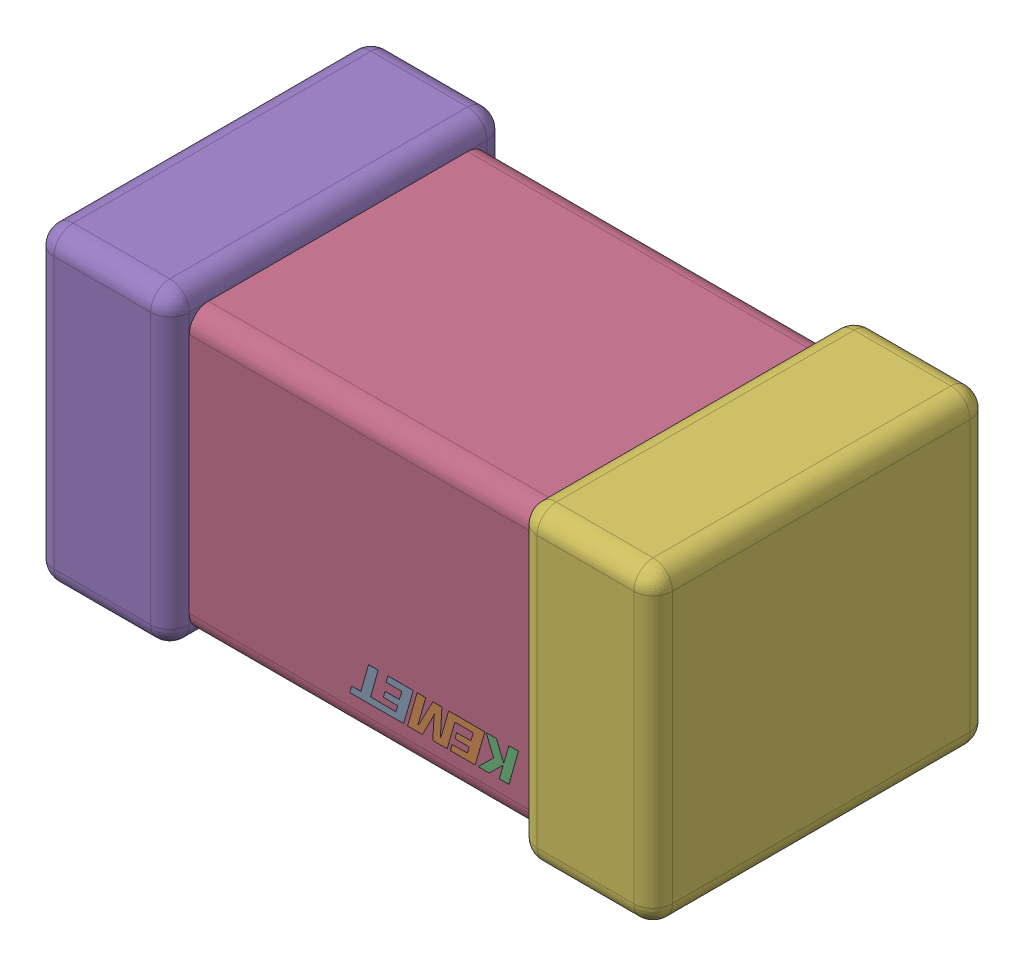
SolidWorks assembly C1.step, configuration Default. Lengths in mm.
Overall size (1.6 0.8 0.87).
3 component instances, 3 part files, 0 mates.
Components (placement in the parent):
- Cap_KEMET_C0603C272M5JACTU_eec.step-1: Cap_KEMET_C0603C272M5JACTU_eec.step [Default] at (46.482 49.403 0) x (-1 0 0) z (0 0 1) size (0.44 0.09 0)
- Cap_KEMET_C0603C272M5JACTU_eec-9.step-1: Cap_KEMET_C0603C272M5JACTU_eec-9.step [Default] at (46.482 49.403 0) x (-1 0 0) z (0 0 1) size (0.9 0.72 0.77)
- Cap_KEMET_C0603C272M5JACTU_eec-10.step-1: Cap_KEMET_C0603C272M5JACTU_eec-10.step [Default] at (46.482 49.403 0) x (-1 0 0) z (0 0 1) size (1.6 0.8 0.87)
